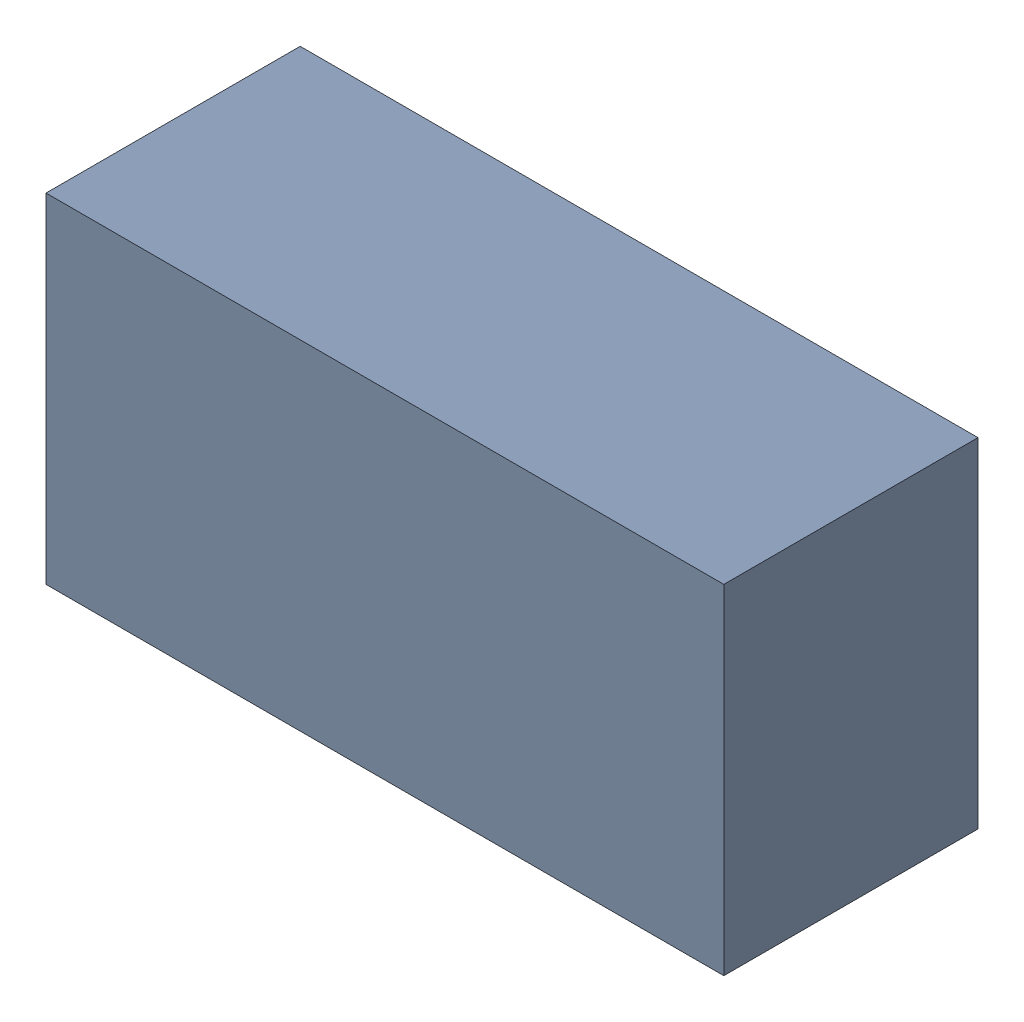
SolidWorks assembly FL1, configuration Standard. Lengths in mm.
Overall size (1.6 0.8 0.6).
2 component instances, 1 part files, 0 mates.
Components (placement in the parent):
- 6074063104-1: 6074063104 [Standard] at (-11.55 18.1 0) size (1.6 0.8 0.6)
  - Extruded-1-1: Extruded-1 [Standard] at origin size (1.6 0.8 0.6)
